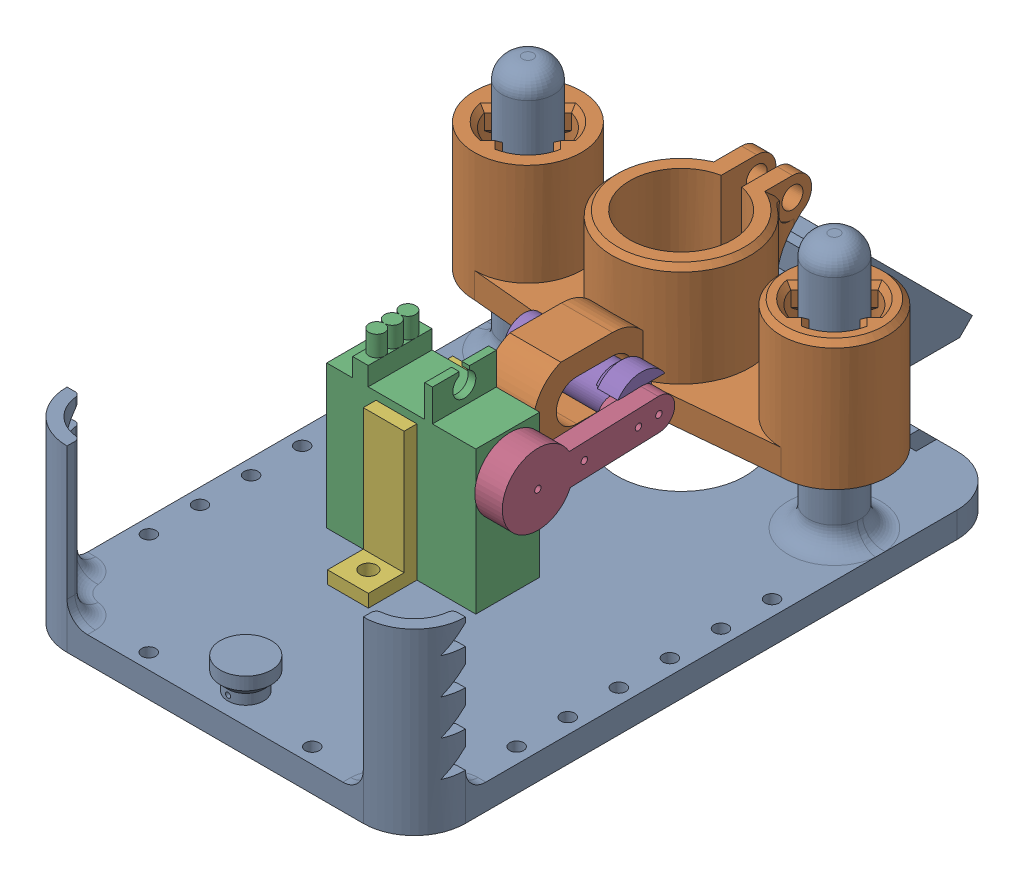
SolidWorks assembly pen subassem, configuration Default. Lengths in mm.
Overall size (80.9 56.24 143.27).
6 component instances, 6 part files, 14 mates.
Components (placement in the parent):
- pen holder servo side-1: pen holder servo side [Default] at (-34.2221 10.8963 51.2144) size (78 55 143.27)
- pen slider-1: pen slider [Default] at (-4.2221 24.753 51.2144) size (80.9 25 54.58)
- servo body sim-1: servo body sim [Default] at (-4.6824 24.9063 94.7096) x (0 1 0) z (0 0 -1) size (41.88 33.7 12.5)
- servo arm sim-1: servo arm sim [Default] at (11.2176 31.9063 94.7096) x (0 -0.035727 0.999362) z (0 -0.999362 -0.035727) size (33.77 5.4 13.92)
- pin follower-1: pin follower [Default] at (7.8176 32.753 71.0247) x (0 0.002704 -0.999996) z (0 0.999996 0.002704) size (9.22 23 11)
- servo clip-1: servo clip [Default] at (-6.2221 11.5588 94.6127) x (0 0 1) z (-1 0 0) size (31.5 26.5 8)
Mates (geometry in assembly coordinates):
- Concentric1: concentric aligned: cylinder of pen holder servo side-1 through (25.7779 60.8963 51.2144) axis (0 -1 0) radius 5.05; cylinder of pen slider-1 through (25.7779 29.753 51.2144) axis (0 -1 0) radius 7
- Concentric2: concentric aligned: cylinder of pen holder servo side-1 through (-34.2221 60.8963 51.2144) axis (0 -1 0) radius 5.05; cylinder of pen slider-1 through (-34.2221 29.753 51.2144) axis (0 -1 0) radius 7
- Concentric3: concentric anti-aligned: cylinder of servo body sim-1 through (9.8176 31.9063 94.7096) axis (-1 0 0) radius 3; cylinder of servo arm sim-1 through (7.6176 31.9063 94.7096) axis (1 0 0) radius 6.9623
- Slot1: slot anti-aligned: plane of servo arm sim-1; plane of pen slider-1 through (0.7779 28.753 51.2144) normal (0 1 0); cylinder of pen slider-1 through (0.7779 32.753 69.6664) axis (-1 0 0) radius 4
- LimitDistance1: limit distance = 13.8467 mm anti-aligned: plane of pen slider-1 through (-34.2221 24.753 51.2144) normal (0 -1 0); plane of pen holder servo side-1 through (-33.2221 10.9063 36.2144) normal (0 1 0)
- Distance6: distance = 0.5 mm anti-aligned: plane of servo body sim-1 through (5.3176 24.9063 94.7096) normal (1 0 0); plane of servo arm sim-1 through (5.8176 31.9063 94.7096) normal (-1 0 0)
- Coincident13: coincident anti-aligned: plane of pen holder servo side-1 through (-33.2221 10.9063 36.2144) normal (0 1 0); plane of servo clip-1 through (-14.2221 10.9063 110.4596) normal (0 -1 0)
- Concentric5: concentric aligned: circle of pen holder servo side-1; cylinder of servo clip-1 through (-10.2221 3.4063 82.9596) axis (0 1 0) radius 1.6
- Concentric6: concentric aligned: cylinder of pen holder servo side-1 through (-10.2221 0.9063 106.4596) axis (0 1 0) radius 1.35; cylinder of servo clip-1 through (-10.2221 3.4063 106.4596) axis (0 1 0) radius 1.6
- Coincident14: coincident anti-aligned: plane of servo arm sim-1 through (5.8176 31.9063 94.7096) normal (-1 0 0); plane of pin follower-1 through (5.8176 32.753 71.0247) normal (1 0 0)
- Concentric8: concentric aligned: cylinder of servo arm sim-1 through (7.6176 32.753 71.0247) axis (1 0 0) radius 0.625; cylinder of pin follower-1 through (-15.1824 32.753 71.0247) axis (1 0 0) radius 1.6
- Coincident16: coincident anti-aligned: plane of servo body sim-1 through (-3.1824 45.1563 100.9596) normal (0 0 1); plane of servo clip-1 through (-14.2221 10.9063 100.9596) normal (0 0 -1)
- Coincident17: coincident anti-aligned: plane of pen holder servo side-1 through (-33.2221 10.9063 36.2144) normal (0 1 0); plane of servo body sim-1 through (-23.8824 10.9063 100.9596) normal (0 -1 0)
- Width1: width anti-aligned: plane of servo body sim-1 through (-4.6824 42.3907 94.7096) normal (-1 0 0); plane of servo clip-1 through (-15.7617 38.9063 105.6935) normal (1 0 0); plane of servo body sim-1 through (-6.2221 11.5588 94.6127) normal (1 0 0); plane of servo clip-1 through (-14.2221 11.5588 94.6127) normal (-1 0 0)
